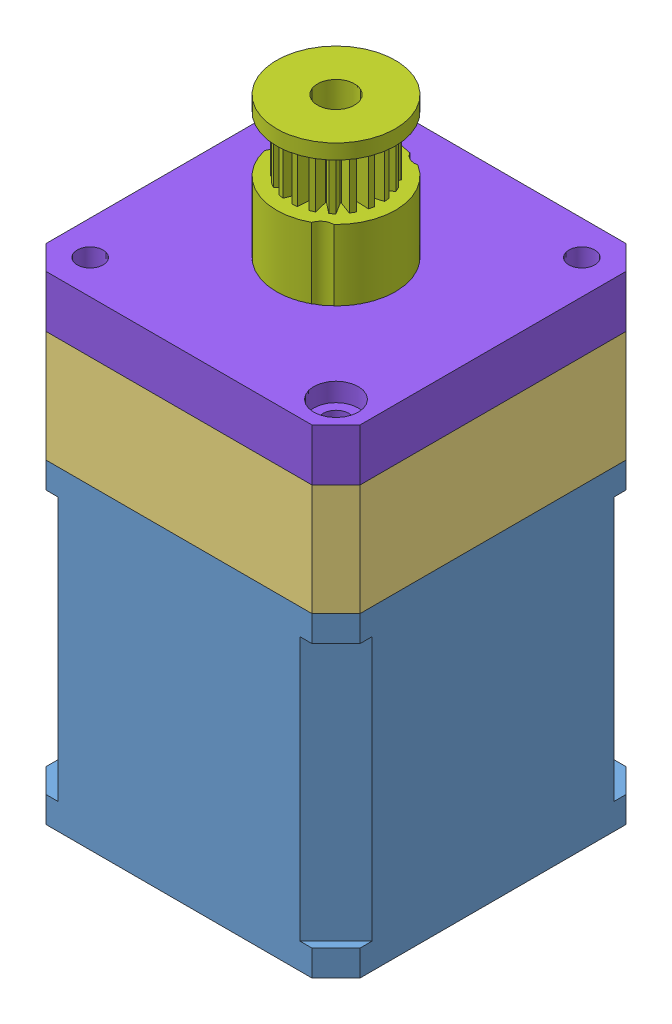
SolidWorks assembly Assem4, configuration Default. Lengths in mm.
Overall size (42.3 83.5 42.3).
10 component instances, 8 part files, 28 mates.
Components (placement in the parent):
- stepper_motor_body-1: stepper_motor_body [Default] at (23.059 -10.0043 45.5579) x (0 0 1) z (0 1 0) size (42.3 42.3 44.5)
- stepper_motor_shaft-1: stepper_motor_shaft [Default] at (23.059 -10.0043 45.5579) x (-0.573139 0 -0.819458) z (0 1 0) size (5 5 74)
- carrier-1: carrier [Default] at (23.0256 55.7186 37.2384) x (0 1 0) z (0 0 1) size (15 42.3 42.3)
- sun-1: sun [Default] at (19.7603 41.196 46.1596) x (0 1 0) z (0.573139 0 0.819458) size (10 10.9 10.9)
- holder-1: holder [Default] at (23.059 34.4957 45.5579) x (0.101692 0 0.994816) z (0 1 0) size (29.49 26.88 13)
- planet-1: planet [Default] at (17.9994 39.1688 55.3892) x (0 1 0) z (-0.433423 0 -0.901191) size (10 13.46 13.49)
- planet-2: planet [Default] at (16.9769 39.1688 36.8112) x (0 1 0) z (0.541312 0 0.840822) size (10 13.46 13.49)
- planet-3: planet [Default] at (33.7025 39.1688 44.108) x (0 1 0) z (-0.644629 0 -0.764495) size (10 13.46 13.49)
- output-1: output [Default] at (23.059 47.4957 45.5579) x (0.101692 0 0.994816) z (0 1 0) size (29.49 26.88 26)
- cap-1: cap [Default] at (31.3785 47.4957 45.5913) x (-1 0 0) z (0 1 0) size (42.3 42.3 7)
Mates (geometry in assembly coordinates):
- Coincident1: coincident: plane of stepper_motor_body-1 through (23.059 -10.0043 45.5579) normal (0 -1 0); circle of stepper_motor_shaft-1
- Coincident2: coincident: circle of stepper_motor_body-1; cylinder of stepper_motor_shaft-1 through (23.059 -10.0043 45.5579) axis (0 1 0) radius 2.5
- Coincident3: coincident: plane of stepper_motor_body-1 through (23.059 32.4957 45.5579) normal (0 1 0); plane of carrier-1 through (23.0256 32.4957 37.2384) normal (0 -1 0)
- Concentric2: concentric: cylinder of stepper_motor_body-1 through (39.609 -10.0043 62.1079) axis (0 1 0) radius 1.75; cylinder of carrier-1 through (39.609 37.4957 62.1079) axis (0 1 0) radius 1.75
- Concentric3: concentric: cylinder of stepper_motor_body-1 through (6.509 -10.0043 29.0079) axis (0 1 0) radius 1.75; cylinder of carrier-1 through (6.509 37.4957 29.0079) axis (0 1 0) radius 1.75
- Concentric4: concentric: cylinder of stepper_motor_shaft-1 through (23.059 -10.0043 45.5579) axis (0 1 0) radius 2.5; cylinder of sun-1 through (23.059 87.4958 45.5579) axis (0 -1 0) radius 2.5
- Coincident7: coincident: plane of stepper_motor_shaft-1 through (21.6262 43.9957 43.5092) normal (-0.984715 0 -0.174174); plane of sun-1 through (21.0104 37.4957 46.9907) normal (0.984715 0 0.174174)
- Coincident8: coincident: plane of stepper_motor_body-1 through (23.059 34.4957 45.5579) normal (0 1 0); plane of holder-1 through (16.4724 34.4957 36.4376) normal (0 -1 0)
- Coincident9: coincident: plane of sun-1 through (23.059 37.4957 45.5579) normal (0 -1 0); plane of holder-1 through (16.4724 37.4957 36.4376) normal (0 1 0)
- Concentric5: concentric: cylinder of holder-1 through (34.2507 37.4957 44.4138) axis (0 -1 0) radius 1.5; cylinder of planet-3 through (34.2507 37.4957 44.4138) axis (0 1 0) radius 1.425
- Concentric6: concentric: cylinder of holder-1 through (18.4539 37.4957 55.8221) axis (0 -1 0) radius 1.5; cylinder of planet-1 through (18.4539 37.4957 55.8221) axis (0 1 0) radius 1.425
- Concentric7: concentric: cylinder of holder-1 through (16.4724 37.4957 36.4376) axis (0 -1 0) radius 1.5; cylinder of planet-2 through (16.4724 37.4957 36.4376) axis (0 1 0) radius 1.425
- Coincident10: coincident: plane of planet-2 through (16.4724 37.4957 36.4376) normal (0 -1 0); plane of planet-3 through (34.2507 37.4957 44.4138) normal (0 -1 0)
- Coincident11: coincident: plane of planet-1 through (18.4539 37.4957 55.8221) normal (0 -1 0); plane of planet-3 through (34.2507 37.4957 44.4138) normal (0 -1 0)
- Coincident12: coincident: plane of holder-1 through (16.4724 37.4957 36.4376) normal (0 1 0); plane of planet-3 through (34.2507 37.4957 44.4138) normal (0 -1 0)
- Concentric8: concentric: circle of stepper_motor_shaft-1; circle of holder-1
- Coincident13: coincident: plane of sun-1 through (23.059 47.4957 45.5579) normal (0 1 0); plane of output-1 through (16.4724 47.4957 36.4376) normal (0 -1 0)
- Concentric9: concentric: cylinder of stepper_motor_shaft-1 through (23.059 -10.0043 45.5579) axis (0 1 0) radius 2.5; cylinder of output-1 through (23.059 47.4957 45.5579) axis (0 1 0) radius 2.5
- Concentric10: concentric: cylinder of planet-3 through (34.2507 37.4957 44.4138) axis (0 1 0) radius 1.425; cylinder of output-1 through (34.2507 50.9957 44.4138) axis (0 -1 0) radius 1.5
- Concentric11: concentric: cylinder of planet-2 through (16.4724 37.4957 36.4376) axis (0 1 0) radius 1.425; cylinder of output-1 through (16.4724 50.9957 36.4376) axis (0 -1 0) radius 1.5
- Concentric12: concentric: cylinder of planet-1 through (18.4539 37.4957 55.8221) axis (0 1 0) radius 1.425; cylinder of output-1 through (18.4539 50.9957 55.8221) axis (0 -1 0) radius 1.5
- Coincident17: coincident: plane of carrier-1 through (23.059 47.4957 28.5579) normal (0 1 0); plane of cap-1 through (31.3785 47.4957 45.5913) normal (0 -1 0)
- Concentric14: concentric: cylinder of carrier-1 through (39.609 37.4957 62.1079) axis (0 1 0) radius 1.75; cylinder of cap-1 through (39.609 51.9957 62.1079) axis (0 -1 0) radius 1.75
- Concentric15: concentric: cylinder of carrier-1 through (6.509 37.4957 29.0079) axis (0 1 0) radius 1.75; cylinder of cap-1 through (6.509 51.9957 29.0079) axis (0 -1 0) radius 1.75
- GearMate6: gear = 200 : 250 mm: circle of planet-3; circle of stepper_motor_shaft-1
- GearMate7: gear = 250 : 200 mm: circle of stepper_motor_shaft-1; circle of planet-2
- GearMate8: gear = 250 : 200 mm: circle of stepper_motor_shaft-1; circle of planet-1
- GearMate9: gear = 250 : 700 mm: circle of carrier-1; circle of planet-2
